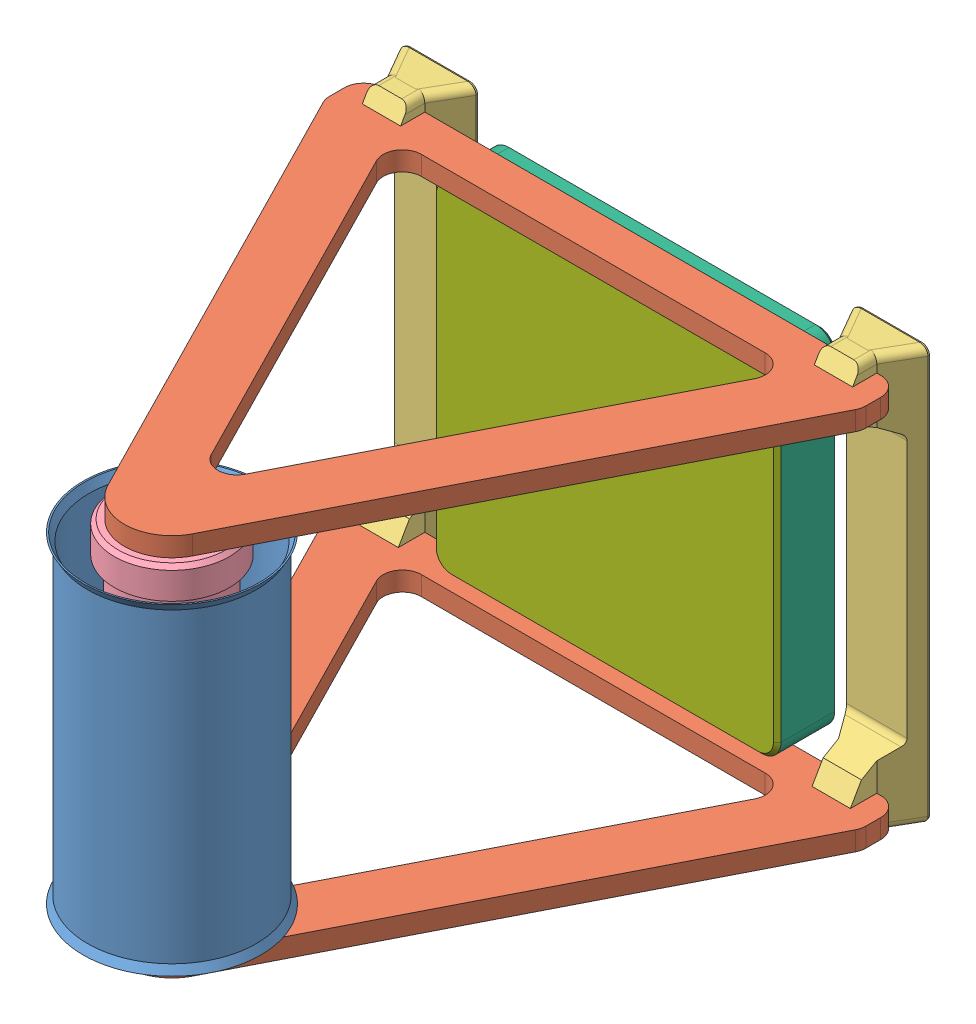
SolidWorks assembly Enclosure Filament Container, configuration Default. Lengths in mm.
Overall size (220 108 239.48).
26 component instances, 18 part files, 36 mates.
Components (placement in the parent):
- Filament Container Extension_v19.step-1: Filament Container Extension_v19.step [Default] at origin size (264.5 145 42.8) (hidden)
  - Component8.step-1: Component8.step [Default] at origin size (201 111.5 39.6) (hidden)
    - CaseBot.step-1: CaseBot.step [Default] at origin size (180 107 26)
    - Axis.step-1: Axis.step [Default] at origin size (108 100 8)
    - Bearing.step-1: Bearing.step [Default] at origin size (22 7 22) (hidden)
    - Bearing.step-2: Bearing.step [Default] at (0 95 0) size (22 7 22) (hidden)
    - Bearing.step-3: Bearing.step [Default] at (-100 0 0) size (22 7 22) (hidden)
    - Bearing.step-4: Bearing.step [Default] at (-100 95 0) size (22 7 22) (hidden)
    - CaseTop.step-1: CaseTop.step [Default] at origin size (175.2 102.2 2)
  - ContainerLatch.step-1: ContainerLatch.step [Default] at origin size (239 122 6)
  - TopPiece.step-1: TopPiece.step [Default] at origin size (245.51 122 12)
  - Foam1.step-1: Foam1.step [Default] at origin size (239 122 2.8)
  - BottomPiece.step-1: BottomPiece.step [Default] at origin size (245 145 19.3)
  - Foam2.step-1: Foam2.step [Default] at origin size (239 122 2.8)
  - FrontLatch.step-1: FrontLatch.step [Default] at origin size (21.6 12 37.2) (hidden)
  - Spacer.step-1: Spacer.step [Default] at origin size (12 11.5 2.8) (hidden)
- Part48^Enclosure Filament Container-1: Part48^Enclosure Filament Container [Default] x (1 0 0) z (0 1 0) size (220 220 84) (virtual)
- Part49^Enclosure Filament Container-1: Part49^Enclosure Filament Container [Default] x (1 0 0) z (0 1 0) size (140 132.4 50) (virtual)
- Part49^Enclosure Filament Container-3: Part49^Enclosure Filament Container [Default] x (-1 0 0) z (0 -1 0) size (140 132.4 50) (virtual)
- Part52^Enclosure Filament Container-1: Part52^Enclosure Filament Container [Default] at (0 0 -28.6) x (1 0 0) z (0 0 -1) size (19.79 108 16.38) (virtual)
- Part52^Enclosure Filament Container-2: Part52^Enclosure Filament Container [Default] at (-118 0 -28.6) x (1 0 0) z (0 0 -1) size (19.79 108 16.38) (virtual)
- Part53^Enclosure Filament Container-1: Part53^Enclosure Filament Container [Default] at (0 45 0) x (-1 0 0) z (0 -1 0) size (30 30 17) (virtual)
- Part53^Enclosure Filament Container-2: Part53^Enclosure Filament Container [Default] at (0 -45 0) x (1 0 0) z (0 1 0) size (30 30 17) (virtual)
- Part54^Enclosure Filament Container-1: Part54^Enclosure Filament Container [Default] x (1 0 0) z (0 1 0) size (16.2 16.2 68) (virtual)
- Part1^Enclosure Filament Container-1: Part1^Enclosure Filament Container [Default] at (0 0 -37.6) x (1 0 0) z (0 0 -1) size (90 90 15) (virtual)
- Part2^Enclosure Filament Container-1: Part2^Enclosure Filament Container [Default] at (0 0 -22.6) x (-1 0 0) z (0 0 1) size (90 90 5) (virtual)
Mates (geometry in assembly coordinates):
- InPlace1: in place: plane of ? through (0 0 0) normal (0 1 0); plane of ? through (0 0 0) normal (0 1 0); moOrthogonalPlaneRef_w of ? through (0 0 0) normal (0 1 0); plane of ? through (0 0 0) normal (0 0 -1); plane of ? through (0 0 0) normal (0 1 0); plane of ? through (0 0 0) normal (1 0 0); plane of ? through (0 0 0) normal (0 1 0); unknown of ?
- Coincident1: coincident aligned: plane of Filament Container Extension_v19.step-1; plane of Part48^Enclosure Filament Container-1
- Coincident2: coincident aligned: moOrthogonalPlaneRef_w of Filament Container Extension_v19.step-1; plane of Part48^Enclosure Filament Container-1 through (0 0 0) normal (0 0 -1)
- Coincident3: coincident anti-aligned: moOrthogonalPlaneRef_w of Filament Container Extension_v19.step-1 through (23.54 -23.54 0) axis (0 0 -1); plane of Part48^Enclosure Filament Container-1 through (0 0 0) normal (1 0 0)
- InPlace2: in place: plane of ? through (0 0 0) normal (0 1 0); plane of ? through (0 0 0) normal (0 0 -1); plane of ? through (0 0 0) normal (1 0 0); unknown of ?
- Coincident4: coincident aligned: 
- Coincident5: coincident aligned: plane of Part49^Enclosure Filament Container-1 through (0 0 0) normal (0 0 -1)
- Coincident6: coincident anti-aligned: plane of Part49^Enclosure Filament Container-1 through (0 0 0) normal (1 0 0)
- InPlace3: in place: plane of ? through (0 0 0) normal (0 1 0); plane of ? through (0 0 0) normal (0 0 -1); plane of ? through (0 0 0) normal (1 0 0); unknown of ?
- Coincident7: coincident aligned: 
- Coincident8: coincident aligned: plane of Part50^Enclosure Filament Container-1 through (0 0 0) normal (0 0 -1)
- Coincident9: coincident anti-aligned: plane of Part50^Enclosure Filament Container-1 through (0 0 0) normal (1 0 0)
- InPlace5: in place: plane of ? through (0 45 -28.6) normal (0 0 -1); plane of ? through (0 0 -28.6) normal (0 0 -1); plane of ? through (0 45 -28.6) normal (0 0 -1); plane of ? through (0 0 -28.6) normal (0 1 0); plane of ? through (0 45 -28.6) normal (0 0 -1); plane of ? through (0 0 -28.6) normal (-1 0 0); plane of ? through (0 45 -28.6) normal (0 0 -1); unknown of Part52^Enclosure Filament Container-1
- Coincident13: coincident aligned: plane of Part49^Enclosure Filament Container-1; plane of Part52^Enclosure Filament Container-1
- Coincident14: coincident aligned: moOrthogonalPlaneRef_w of Part49^Enclosure Filament Container-1 through (0 0 -28.6) normal (0 -1 0); plane of Part52^Enclosure Filament Container-1 through (0 0 -28.6) normal (0 -1 0)
- Coincident15: coincident anti-aligned: moOrthogonalPlaneRef_w of Part49^Enclosure Filament Container-1 through (0 0 -28.6) normal (-1 0 0); plane of Part52^Enclosure Filament Container-1 through (0 0 -28.6) normal (1 0 0)
- InPlace6: in place: plane of ? through (0 45 0) normal (0 -1 0); plane of Part53^Enclosure Filament Container-1 through (0 45 0) normal (0 -1 0); plane of ? through (0 45 0) normal (0 -1 0); plane of Part53^Enclosure Filament Container-1 through (0 45 0) normal (0 0 -1); plane of ? through (0 45 0) normal (0 -1 0); plane of Part53^Enclosure Filament Container-1 through (0 45 0) normal (-1 0 0); plane of ? through (0 45 0) normal (0 -1 0); unknown of Part53^Enclosure Filament Container-1
- Coincident1: coincident aligned: plane of Part49^Enclosure Filament Container-1; plane of Part53^Enclosure Filament Container-1
- Coincident2: coincident aligned: moOrthogonalPlaneRef_w of Part49^Enclosure Filament Container-1 through (0 45 0) normal (0 0 -1); plane of Part53^Enclosure Filament Container-1 through (0 45 0) normal (0 0 -1)
- Coincident3: coincident anti-aligned: moOrthogonalPlaneRef_w of Part49^Enclosure Filament Container-1 through (0 45 0) normal (1 0 0); plane of Part53^Enclosure Filament Container-1 through (0 45 0) normal (-1 0 0)
- InPlace7: in place: plane of ? through (0 0 0) normal (0 1 0); plane of ? through (0 0 0) normal (0 0 -1); plane of ? through (0 0 0) normal (1 0 0); unknown of ?
- Coincident4: coincident aligned: 
- Coincident5: coincident aligned: plane of Part54^Enclosure Filament Container-1 through (0 0 0) normal (0 0 -1)
- Coincident6: coincident anti-aligned: plane of Part54^Enclosure Filament Container-1 through (0 0 0) normal (1 0 0)
- InPlace8: in place: plane of ? through (0 0 0) normal (0 0 1); plane of ? through (0 0 0) normal (0 1 0); plane of ? through (0 0 0) normal (1 0 0); unknown of ?
- Coincident7: coincident aligned: 
- Coincident8: coincident aligned: plane of Part55^Enclosure Filament Container-1 through (0 0 0) normal (0 1 0)
- Coincident9: coincident anti-aligned: plane of Part55^Enclosure Filament Container-1 through (0 0 0) normal (1 0 0)
- InPlace9: in place: plane of Part52^Enclosure Filament Container-1 through (0 0 -38.6) normal (0 0 -1); plane of ? through (0 0 -38.6) normal (0 0 -1); plane of Part52^Enclosure Filament Container-1 through (0 0 -38.6) normal (0 0 -1); plane of ? through (0 0 -38.6) normal (0 1 0); plane of Part52^Enclosure Filament Container-1 through (0 0 -38.6) normal (0 0 -1); plane of ? through (0 0 -38.6) normal (-1 0 0); plane of Part52^Enclosure Filament Container-1 through (0 0 -37.6) normal (0 0 -1); unknown of Part1^Enclosure Filament Container-1
- Coincident1: coincident aligned: plane of Part52^Enclosure Filament Container-1; plane of Part1^Enclosure Filament Container-1
- Coincident2: coincident aligned: moOrthogonalPlaneRef_w of Part52^Enclosure Filament Container-1 through (0 0 -37.6) normal (0 -1 0); plane of Part1^Enclosure Filament Container-1 through (0 0 -37.6) normal (0 -1 0)
- Coincident3: coincident anti-aligned: moOrthogonalPlaneRef_w of Part52^Enclosure Filament Container-1 through (0 0 -37.6) normal (-1 0 0); plane of Part1^Enclosure Filament Container-1 through (0 0 -37.6) normal (1 0 0)
- InPlace10: in place: plane of ? through (40 -40 -28.6) normal (0 0 1); plane of ? through (0 0 -28.6) normal (0 0 1); plane of ? through (40 -40 -28.6) normal (0 0 1); plane of ? through (0 0 -28.6) normal (0 1 0); plane of ? through (40 -40 -28.6) normal (0 0 1); plane of ? through (0 0 -28.6) normal (1 0 0); plane of Part1^Enclosure Filament Container-1 through (40 -40 -22.6) normal (0 0 1); unknown of Part2^Enclosure Filament Container-1
- Coincident4: coincident aligned: plane of Part1^Enclosure Filament Container-1; plane of Part2^Enclosure Filament Container-1
- Coincident5: coincident aligned: moOrthogonalPlaneRef_w of Part1^Enclosure Filament Container-1 through (0 0 -22.6) normal (0 -1 0); plane of Part2^Enclosure Filament Container-1 through (0 0 -22.6) normal (0 -1 0)
- Coincident6: coincident anti-aligned: moOrthogonalPlaneRef_w of Part1^Enclosure Filament Container-1 through (0 0 -22.6) normal (1 0 0); plane of Part2^Enclosure Filament Container-1 through (0 0 -22.6) normal (-1 0 0)
